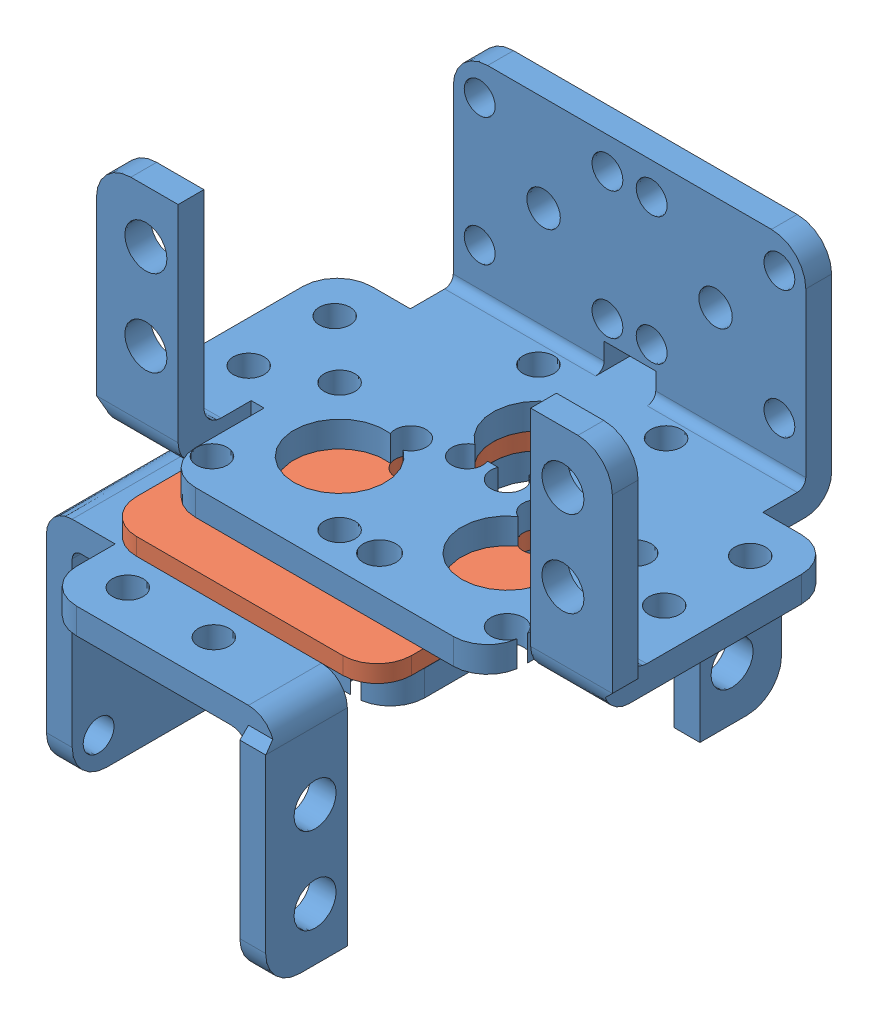
SolidWorks assembly box1_left, configuration Predeterminado. Lengths in mm.
Overall size (60 56 60).
3 component instances, 2 part files, 6 mates.
Components (placement in the parent):
- multi_purpose_bracket-1: multi_purpose_bracket [Predeterminado] at (-9.3022 -17.1692 -4.5) size (60 27 38.5)
- multi_purpose_bracket-2: multi_purpose_bracket [Predeterminado] at (-21.5222 -19.1692 4.1) x (0 0 1) z (1 0 0) size (60 27 38.5)
- box1_supplement-1: box1_supplement [Predeterminado] at (-13.8022 -19.1692 3.915) x (-1 0 0) z (0 0 -1) size (32 2 41.37)
Mates (geometry in assembly coordinates):
- Concéntrica1: concentric aligned: circle of multi_purpose_bracket-1; circle of multi_purpose_bracket-2
- Paralelo1: parallel aligned: plane of multi_purpose_bracket-1 through (-38.3022 -14.1692 -7.25) normal (-1 0 0); plane of multi_purpose_bracket-2 through (-36.2722 -46.1692 24.6) normal (-1 0 0)
- Concéntrica3: concentric aligned: cylinder of multi_purpose_bracket-2 through (-9.3022 -19.1681 -5.65) axis (0 -1 0) radius 5.3; cylinder of box1_supplement-1 through (-9.3022 -17.1692 -5.65) axis (0 -1 0) radius 5.3
- Concéntrica4: concentric aligned: cylinder of multi_purpose_bracket-2 through (-1.8776 -24.1692 1.7746) axis (0 1 0) radius 1.8; cylinder of box1_supplement-1 through (-1.8776 -19.1702 1.7746) axis (0 1 0) radius 1.8
- Coincidente1: coincident anti-aligned: plane of multi_purpose_bracket-2 through (-21.5222 -19.1692 4.1) normal (0 1 0); plane of box1_supplement-1 through (-13.8022 -19.1692 3.915) normal (0 -1 0)
- Coincidente2: coincident anti-aligned: plane of multi_purpose_bracket-1 through (-9.3022 -17.1692 -4.5) normal (0 -1 0); plane of box1_supplement-1 through (-13.8022 -17.1692 3.915) normal (0 1 0)
